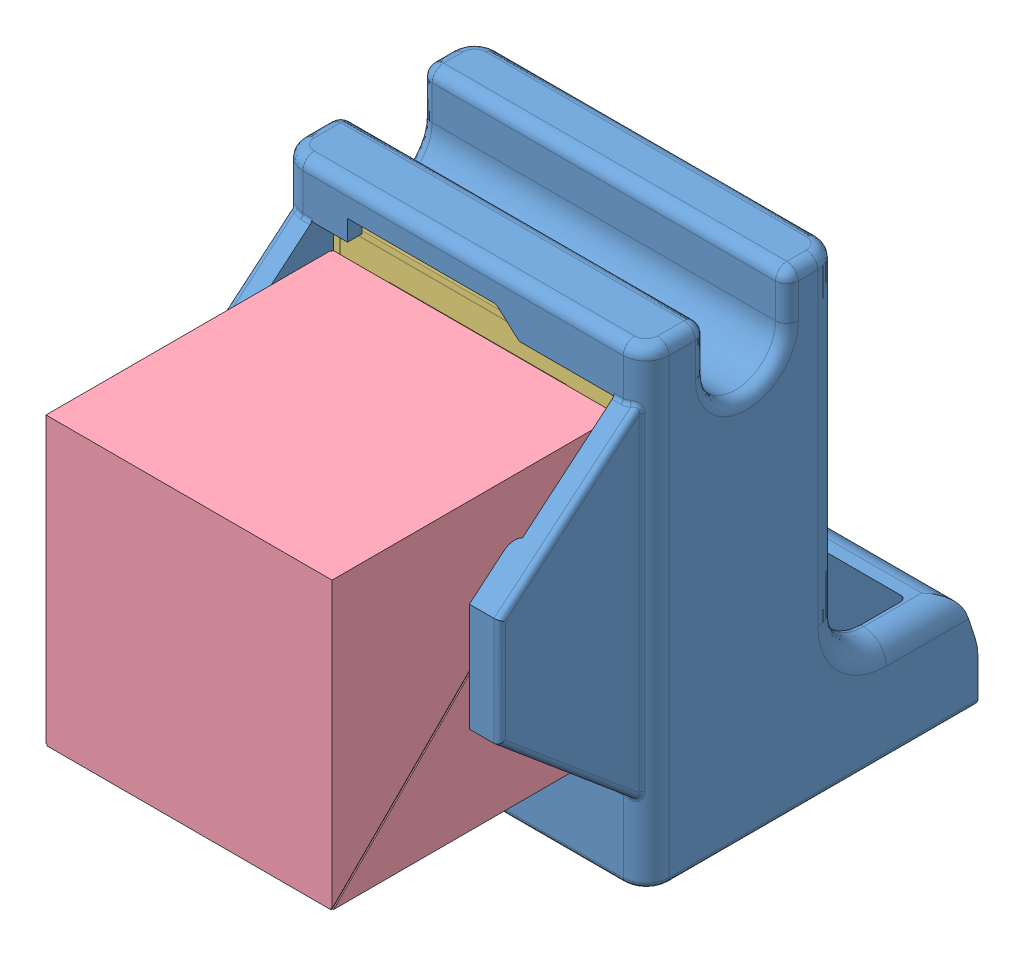
SolidWorks assembly metal_assm, configuration Default. Lengths in mm.
Overall size (32 41 52.95).
4 component instances, 4 part files, 9 mates.
Components (placement in the parent):
- metal-1: metal [默认] at (60.8304 13.0639 -22.1466) size (32 41 41)
- MainBoard.step-1: MainBoard.step [默认] at (73.9749 15.534 -18.8429) x (0 1 0) z (0 0 1) size (29.49 23.87 11.19)
- ExtendBoard.step-1: ExtendBoard.step [默认] at (47.7114 19.9661 -11.6466) x (0 1 0) z (0 0 -1) size (31.51 26.49 8.62)
- 25MM棱镜-1: 25MM棱镜 [默认] at (60.8304 22.3058 3.8047) size (25 25 25)
Mates (geometry in assembly coordinates):
- 平行1: parallel anti-aligned: plane of metal-1 through (60.8304 13.0639 -21.9466) normal (0 0 1); plane of MainBoard.step-1 through (64.3329 21.437 -20.1466) normal (0 0 -1)
- 平行2: parallel aligned: plane of metal-1 through (44.8304 22.0639 -7.6466) normal (-1 0 0); plane of MainBoard.step-1 through (49.0829 40.68 -20.1466) normal (-1 0 0)
- 重合1: coincident anti-aligned: plane of metal-1 through (60.8304 13.0639 -20.1466) normal (0 0 1); plane of MainBoard.step-1 through (64.3329 21.437 -20.1466) normal (0 0 -1)
- 宽度1: width anti-aligned: plane of MainBoard.step-1 through (49.0829 40.68 -20.1466) normal (-1 0 0); plane of metal-1 through (72.5779 22.699 -20.1466) normal (1 0 0); plane of MainBoard.step-1 through (49.0304 22.2639 -20.1466) normal (1 0 0); plane of metal-1 through (72.6304 22.2639 -20.1466) normal (-1 0 0)
- 宽度3: width anti-aligned: plane of ExtendBoard.step-1 through (47.7114 19.9661 -10.5552) normal (-1 0 0); plane of metal-1 through (73.9494 49.3541 -10.5552) normal (1 0 0); plane of ExtendBoard.step-1 through (47.6304 20.0058 -11.6466) normal (1 0 0); plane of metal-1 through (74.0304 20.0058 -11.6466) normal (-1 0 0)
- 重合2: coincident anti-aligned: plane of metal-1 through (60.8304 13.0639 -11.6466) normal (0 0 1); plane of ExtendBoard.step-1 through (47.7114 19.9661 -11.6466) normal (0 0 -1)
- 宽度4: width anti-aligned: plane of 25MM棱镜-1 through (73.3304 47.3058 16.3047) normal (1 0 0); plane of metal-1 through (48.3304 47.3058 16.3047) normal (-1 0 0); plane of 25MM棱镜-1 through (73.3804 13.0639 -22.1466) normal (-1 0 0); plane of metal-1 through (48.2804 13.0639 -22.1466) normal (1 0 0)
- 宽度5: width aligned: plane of 25MM棱镜-1 through (73.3304 47.3058 16.3047) normal (1 0 0); plane of metal-1 through (48.3304 47.3058 16.3047) normal (-1 0 0); plane of 25MM棱镜-1 through (48.2804 13.0639 -22.1466) normal (1 0 0); plane of metal-1 through (73.3804 13.0639 -22.1466) normal (-1 0 0)
- 宽度6: width anti-aligned: plane of 25MM棱镜-1 through (60.8304 22.3058 3.8047) normal (0 -1 0); plane of metal-1 through (60.8304 47.3058 3.8047) normal (0 1 0); plane of 25MM棱镜-1 through (47.6304 20.0058 -11.6466) normal (0 1 0); plane of metal-1 through (65.7304 49.6058 -11.6466) normal (0 -1 0)
